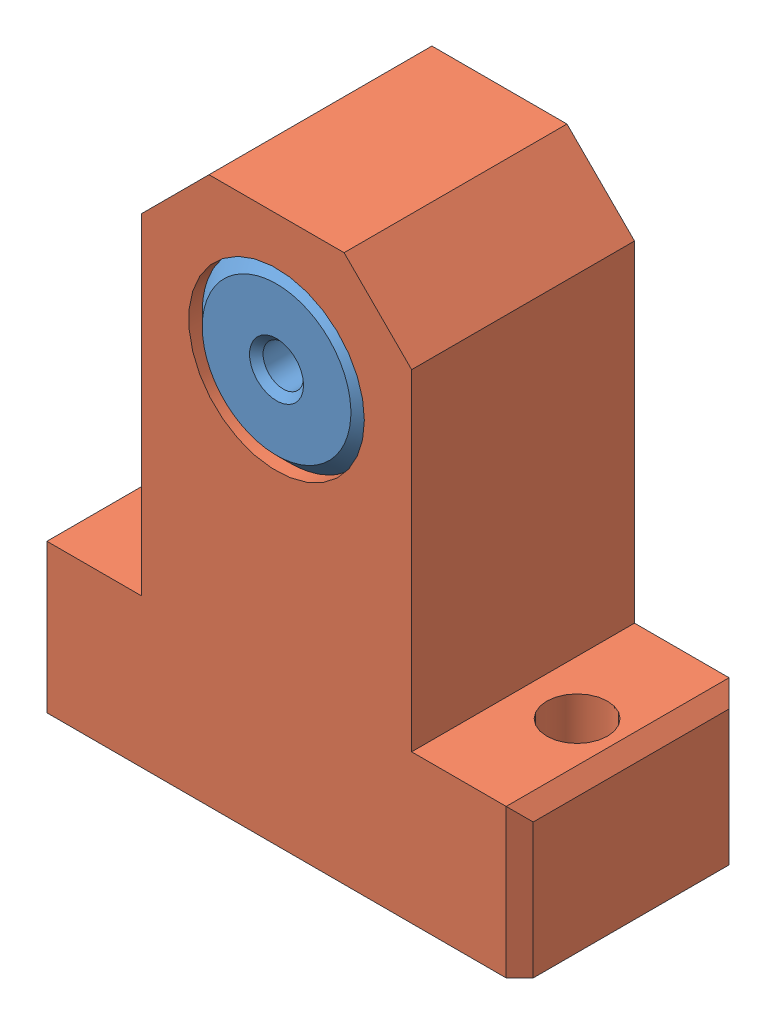
SolidWorks assembly 丝杆尾固定^摩擦系数测量, configuration 默认. Lengths in mm.
Overall size (20 40.5 26.5).
3 component instances, 2 part files, 4 mates.
Components (placement in the parent):
- D13d3h5轴承-1: D13d3h5轴承 [默认] at (3.2707 20.1072 3.25) size (13 13 5)
- 丝杆固定座-1: 丝杆固定座 [默认] at (3.2707 -10.3928 11.5) size (20 40.5 26.5)
- D13d3h5轴承-2: D13d3h5轴承 [默认] at (3.2707 20.1072 14.75) size (13 13 5)
Mates (geometry in assembly coordinates):
- 重合1: coincident anti-aligned: plane of D13d3h5轴承-1 through (3.2707 20.1072 8.25) normal (0 0 1); plane of 丝杆固定座-1 through (3.2707 20.1072 8.25) normal (0 0 -1)
- 重合2: coincident anti-aligned: plane of 丝杆固定座-1 through (3.2707 20.1072 14.75) normal (0 0 1); plane of D13d3h5轴承-2 through (3.2707 20.1072 14.75) normal (0 0 -1)
- 同心1: concentric aligned: circle of D13d3h5轴承-1; circle of 丝杆固定座-1
- 同心2: concentric anti-aligned: circle of 丝杆固定座-1; circle of D13d3h5轴承-2
